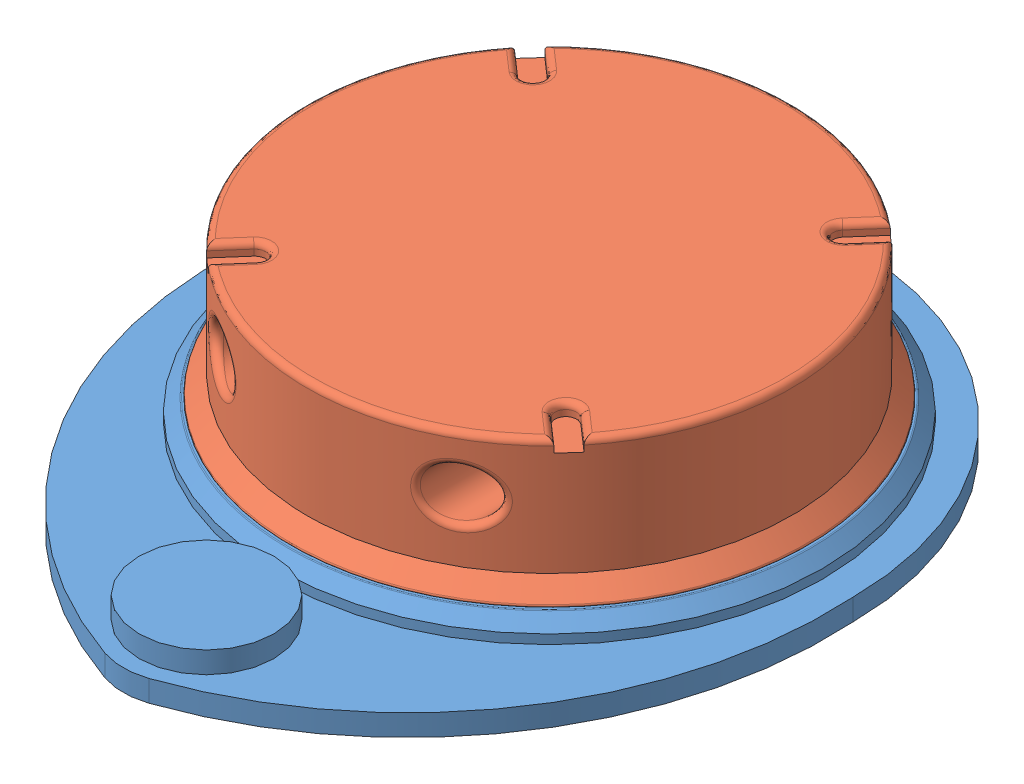
SolidWorks assembly XV11-main, configuration Default. Lengths in mm.
Overall size (99.25 29.09 118.97).
2 component instances, 2 part files, 2 mates.
Components (placement in the parent):
- base-plate-1: base-plate [Default] at (-54.8605 13.6206 9.712) size (99.25 7 118.97)
- revolving-body-1: revolving-body [Default] at (-54.8605 20.1206 9.712) size (84.29 22.09 84.29)
Mates (geometry in assembly coordinates):
- Coincident1: coincident anti-aligned: plane of base-plate-1 through (-54.8605 17.1206 9.712) normal (0 1 0); plane of revolving-body-1 through (-54.8605 17.1206 9.712) normal (0 -1 0)
- Concentric1: concentric anti-aligned: circle of base-plate-1; circle of revolving-body-1
